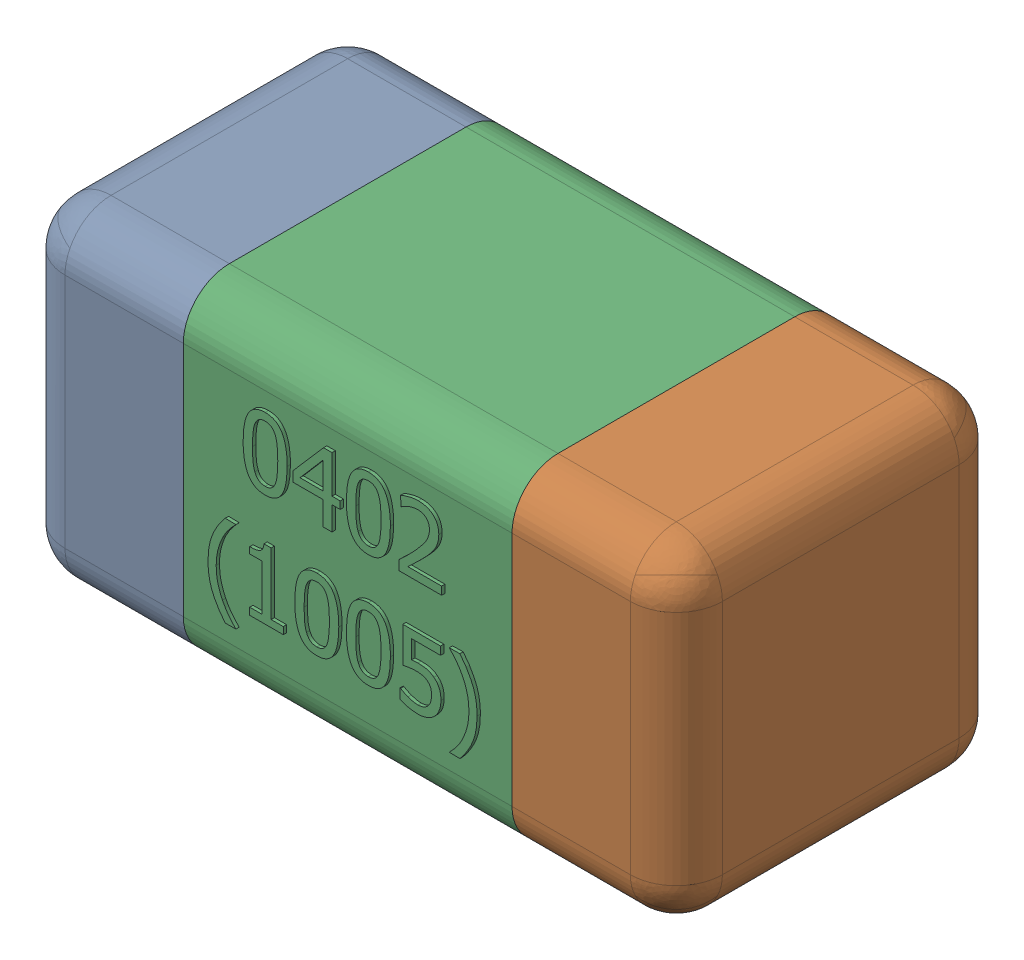
SolidWorks assembly C18, configuration Standard. Lengths in mm.
Overall size (1.01 0.51 0.51).
4 component instances, 3 part files, 0 mates.
Components (placement in the parent):
- C18-subassembly-1-1: C18-subassembly-1 [Standard] at (-1.6999 -8.5 0) x (1 0 0) z (0 0 1) size (1.01 0.51 0.51)
  - User Library-0402_Cap-1: User Library-0402_Cap [Standard] at origin size (0.26 0.51 0.51)
  - User Library-0402_Cap-1-1: User Library-0402_Cap-1 [Standard] at origin size (0.26 0.5 0.51)
  - User Library-0402_Cap-2-1: User Library-0402_Cap-2 [Standard] at origin size (0.5 0.5 0.51)
